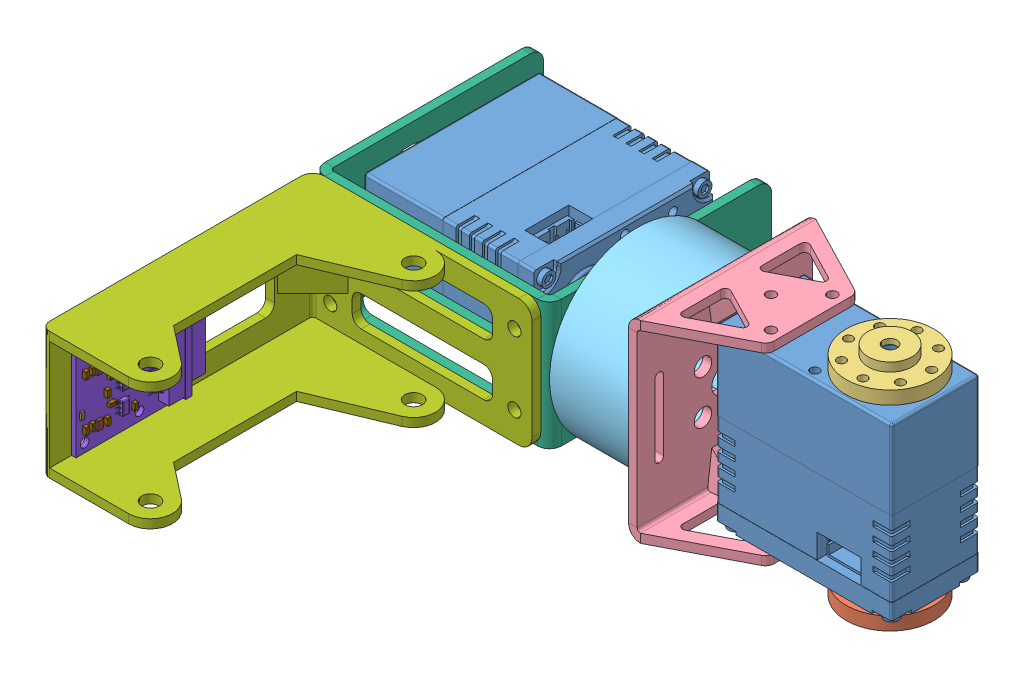
SolidWorks assembly wrist, configuration 默认. Lengths in mm.
Overall size (129.18 52.6 112.65).
74 component instances, 12 part files, 18 mates.
Components (placement in the parent):
- 舵机-1: 舵机 [默认] at origin size (43.48 52.6 27.66)
  - 舵机-1: 舵机 [默认] at origin size (40 51.4 20)
  - 副舵盘-1: 副舵盘 [默认] at (9.65 -0.8 0) x (-0.933258 0 -0.359207) z (-0.359207 0 0.933258) size (20 5 20)
  - 主舵盘-1: 主舵盘 [默认] at (9.65 40.8 0) x (0.838844 0 0.544372) z (-0.544372 0 0.838844) size (20 5 20)
- 短U支架-1: 短U支架 [默认] at (-28 20 0) x (0 1 0) z (0 0 -1) size (44 22 40)
- 45号舵机连接管-1: 45号舵机连接管 [默认] at (-48 20 0) x (0 -1 0) z (0 0 1) size (40 18 40)
- 转向舵机支架-1: 转向舵机支架 [默认] at (-75 20 18) x (1 0 0) z (0 -1 0) size (54 50.65 29)
- 舵机-2: 舵机 [默认] at (-60 20 -9.65) x (0 0 1) z (0 -1 0) size (40 51.4 20)
- 摄像头支架-1: 摄像头支架 [默认] at (-75 20 22) x (-1 0 0) z (0 1 0) size (52 62 29)
- 摄像头-1: 摄像头 [默认] at (-99 20 65) x (0 -1 0) z (0 0 -1) size (25 9.2 28)
  - 摄像头-1: 摄像头 [默认] at origin size (25 9.2 28)
  - 0603电容-2: 0603电容 [默认] at (-25.6955 -0.01 -49.0268) x (1 0 0) z (0 -1 0) size (1.6 0.82 0.82)
    - C_0603^0603电容-1: C_0603^0603电容 [默认] at (34.005 43.815 0) x (-1 0 0) z (0 0 1) size (1.6 0.82 0.82) (virtual)
      - C_0603-9^C_0603_0603电容-1: C_0603-9^C_0603_0603电容 [默认] at origin size (1.6 0.82 0.82) (virtual)
  - 0603电容-3: 0603电容 [默认] at (-42.3062 -0.01 -47.0667) x (1 0 0) z (0 -1 0) size (1.6 0.82 0.82)
    - C_0603^0603电容-1: C_0603^0603电容 [默认] at (34.005 43.815 0) x (-1 0 0) z (0 0 1) size (1.6 0.82 0.82) (virtual)
      - C_0603-9^C_0603_0603电容-1: C_0603-9^C_0603_0603电容 [默认] at origin size (1.6 0.82 0.82) (virtual)
  - 0603电容-7: 0603电容 [默认] at (49.2456 -0.01 -38.1328) x (0 0 1) z (0 -1 0) size (1.6 0.82 0.82)
    - C_0603^0603电容-1: C_0603^0603电容 [默认] at (34.005 43.815 0) x (-1 0 0) z (0 0 1) size (1.6 0.82 0.82) (virtual)
      - C_0603-9^C_0603_0603电容-1: C_0603-9^C_0603_0603电容 [默认] at origin size (1.6 0.82 0.82) (virtual)
  - 0603电容-10: 0603电容 [默认] at (-25.4606 -0.01 -42.7048) x (1 0 0) z (0 -1 0) size (1.6 0.82 0.82)
    - C_0603^0603电容-1: C_0603^0603电容 [默认] at (34.005 43.815 0) x (-1 0 0) z (0 0 1) size (1.6 0.82 0.82) (virtual)
      - C_0603-9^C_0603_0603电容-1: C_0603-9^C_0603_0603电容 [默认] at origin size (1.6 0.82 0.82) (virtual)
  - 0603电容-12: 0603电容 [默认] at (-26.2671 -0.01 -53.9256) x (1 0 0) z (0 -1 0) size (1.6 0.82 0.82)
    - C_0603^0603电容-1: C_0603^0603电容 [默认] at (34.005 43.815 0) x (-1 0 0) z (0 0 1) size (1.6 0.82 0.82) (virtual)
      - C_0603-9^C_0603_0603电容-1: C_0603-9^C_0603_0603电容 [默认] at origin size (1.6 0.82 0.82) (virtual)
  - 0805电容-1: 0805电容 [默认] at (51.4431 -0.01 78.819) x (-1 0 0) z (0 -1 0) size (1.22 2 0.52)
    - C_0805^0805电容-1: C_0805^0805电容 [默认] at (59.563 77.597 0) x (0 1 0) z (0 0 1) size (2 1.22 0.52) (virtual)
      - C_0805-5^C_0805_0805电容-1: C_0805-5^C_0805_0805电容 [默认] at origin size (2 1.22 0.52) (virtual)
  - 0805电阻-1: 0805电阻 [默认] at (115.7364 0 -119.6397) x (0 0 1) z (0 -1 0) size (1.25 2 0.5)
    - R_0805^0805电阻-1: R_0805^0805电阻 [默认] at (112.776 107.442 0) x (0 1 0) z (0 0 1) size (2 1.25 0.5) (virtual)
      - R_0805-21^R_0805_0805电阻-1: R_0805-21^R_0805_0805电阻 [默认] at origin size (2 1.25 0.5) (virtual)
  - 0603电阻-3: 0603电阻 [默认] at (118.0517 0 -149.4378) x (0 0 1) z (0 -1 0) size (0.8 1.6 0.4)
    - R_0603^0603电阻-1: R_0603^0603电阻 [默认] at (138.684 113.411 0) x (0 1 0) z (0 0 1) size (1.6 0.8 0.4) (virtual)
      - R_0603-25^R_0603_0603电阻-1: R_0603-25^R_0603_0603电阻 [默认] at origin size (1.6 0.8 0.4) (virtual)
  - 0603电阻-4: 0603电阻 [默认] at (-106.3314 1 -147.3108) x (0 0 1) z (0 1 0) size (0.8 1.6 0.4)
    - R_0603^0603电阻-1: R_0603^0603电阻 [默认] at (138.684 113.411 0) x (0 1 0) z (0 0 1) size (1.6 0.8 0.4) (virtual)
      - R_0603-25^R_0603_0603电阻-1: R_0603-25^R_0603_0603电阻 [默认] at origin size (1.6 0.8 0.4) (virtual)
  - 0603电阻-5: 0603电阻 [默认] at (134.1937 0 114.6319) x (-1 0 0) z (0 -1 0) size (0.8 1.6 0.4)
    - R_0603^0603电阻-1: R_0603^0603电阻 [默认] at (138.684 113.411 0) x (0 1 0) z (0 0 1) size (1.6 0.8 0.4) (virtual)
      - R_0603-25^R_0603_0603电阻-1: R_0603-25^R_0603_0603电阻 [默认] at origin size (1.6 0.8 0.4) (virtual)
  - 0603电容-14: 0603电容 [默认] at (-26.2671 -0.01 -52.4256) x (1 0 0) z (0 -1 0) size (1.6 0.82 0.82)
    - C_0603^0603电容-1: C_0603^0603电容 [默认] at (34.005 43.815 0) x (-1 0 0) z (0 0 1) size (1.6 0.82 0.82) (virtual)
      - C_0603-9^C_0603_0603电容-1: C_0603-9^C_0603_0603电容 [默认] at origin size (1.6 0.82 0.82) (virtual)
  - 0603电容-15: 0603电容 [默认] at (-30.4606 -0.01 -42.7048) x (1 0 0) z (0 -1 0) size (1.6 0.82 0.82)
    - C_0603^0603电容-1: C_0603^0603电容 [默认] at (34.005 43.815 0) x (-1 0 0) z (0 0 1) size (1.6 0.82 0.82) (virtual)
      - C_0603-9^C_0603_0603电容-1: C_0603-9^C_0603_0603电容 [默认] at origin size (1.6 0.82 0.82) (virtual)
  - 0603电容-16: 0603电容 [默认] at (-35.4606 -0.01 -42.7048) x (1 0 0) z (0 -1 0) size (1.6 0.82 0.82)
    - C_0603^0603电容-1: C_0603^0603电容 [默认] at (34.005 43.815 0) x (-1 0 0) z (0 0 1) size (1.6 0.82 0.82) (virtual)
      - C_0603-9^C_0603_0603电容-1: C_0603-9^C_0603_0603电容 [默认] at origin size (1.6 0.82 0.82) (virtual)
  - 0603电容-17: 0603电容 [默认] at (-37.2671 -0.01 -53.9256) x (1 0 0) z (0 -1 0) size (1.6 0.82 0.82)
    - C_0603^0603电容-1: C_0603^0603电容 [默认] at (34.005 43.815 0) x (-1 0 0) z (0 0 1) size (1.6 0.82 0.82) (virtual)
      - C_0603-9^C_0603_0603电容-1: C_0603-9^C_0603_0603电容 [默认] at origin size (1.6 0.82 0.82) (virtual)
  - 0603电容-18: 0603电容 [默认] at (-37.2671 -0.01 -52.4256) x (1 0 0) z (0 -1 0) size (1.6 0.82 0.82)
    - C_0603^0603电容-1: C_0603^0603电容 [默认] at (34.005 43.815 0) x (-1 0 0) z (0 0 1) size (1.6 0.82 0.82) (virtual)
      - C_0603-9^C_0603_0603电容-1: C_0603-9^C_0603_0603电容 [默认] at origin size (1.6 0.82 0.82) (virtual)
  - 0805电阻-2: 0805电阻 [默认] at (104.7364 0 -119.6397) x (0 0 1) z (0 -1 0) size (1.25 2 0.5)
    - R_0805^0805电阻-1: R_0805^0805电阻 [默认] at (112.776 107.442 0) x (0 1 0) z (0 0 1) size (2 1.25 0.5) (virtual)
      - R_0805-21^R_0805_0805电阻-1: R_0805-21^R_0805_0805电阻 [默认] at origin size (2 1.25 0.5) (virtual)
  - 0603电容-19: 0603电容 [默认] at (-31.1955 -0.01 -49.0268) x (1 0 0) z (0 -1 0) size (1.6 0.82 0.82)
    - C_0603^0603电容-1: C_0603^0603电容 [默认] at (34.005 43.815 0) x (-1 0 0) z (0 0 1) size (1.6 0.82 0.82) (virtual)
      - C_0603-9^C_0603_0603电容-1: C_0603-9^C_0603_0603电容 [默认] at origin size (1.6 0.82 0.82) (virtual)
  - 0603电容-20: 0603电容 [默认] at (-36.6955 -0.01 -49.0268) x (1 0 0) z (0 -1 0) size (1.6 0.82 0.82)
    - C_0603^0603电容-1: C_0603^0603电容 [默认] at (34.005 43.815 0) x (-1 0 0) z (0 0 1) size (1.6 0.82 0.82) (virtual)
      - C_0603-9^C_0603_0603电容-1: C_0603-9^C_0603_0603电容 [默认] at origin size (1.6 0.82 0.82) (virtual)
  - 0603电容-21: 0603电容 [默认] at (43.7456 -0.01 -38.1328) x (0 0 1) z (0 -1 0) size (1.6 0.82 0.82)
    - C_0603^0603电容-1: C_0603^0603电容 [默认] at (34.005 43.815 0) x (-1 0 0) z (0 0 1) size (1.6 0.82 0.82) (virtual)
      - C_0603-9^C_0603_0603电容-1: C_0603-9^C_0603_0603电容 [默认] at origin size (1.6 0.82 0.82) (virtual)
  - 0603电容-22: 0603电容 [默认] at (38.2456 -0.01 -38.1328) x (0 0 1) z (0 -1 0) size (1.6 0.82 0.82)
    - C_0603^0603电容-1: C_0603^0603电容 [默认] at (34.005 43.815 0) x (-1 0 0) z (0 0 1) size (1.6 0.82 0.82) (virtual)
      - C_0603-9^C_0603_0603电容-1: C_0603-9^C_0603_0603电容 [默认] at origin size (1.6 0.82 0.82) (virtual)
  - 0603电阻-6: 0603电阻 [默认] at (132.6937 0 114.6319) x (-1 0 0) z (0 -1 0) size (0.8 1.6 0.4)
    - R_0603^0603电阻-1: R_0603^0603电阻 [默认] at (138.684 113.411 0) x (0 1 0) z (0 0 1) size (1.6 0.8 0.4) (virtual)
      - R_0603-25^R_0603_0603电阻-1: R_0603-25^R_0603_0603电阻 [默认] at origin size (1.6 0.8 0.4) (virtual)
Mates (geometry in assembly coordinates):
- 重合1: coincident anti-aligned: plane of 舵机-1/舵机-1 through (0 0 0) normal (0 -1 0); plane of 短U支架-1 through (-28 0 0) normal (0 1 0)
- 同心1: concentric anti-aligned: circle of 舵机-1/舵机-1; circle of 短U支架-1
- 同心2: concentric anti-aligned: circle of 舵机-1/舵机-1; circle of 短U支架-1
- 重合2: coincident anti-aligned: plane of 短U支架-1 through (-30 20 0) normal (-1 0 0); plane of 60cm连接管-1 through (-30 20 0) normal (1 0 0)
- 同心3: concentric anti-aligned: circle of 短U支架-1; circle of 60cm连接管-1
- 同心4: concentric anti-aligned: circle of 短U支架-1; circle of 60cm连接管-1
- 重合5: coincident anti-aligned: plane of 60cm连接管-1 through (-48 20 0) normal (-1 0 0); plane of 转向舵机支架-1 through (-48 20 18) normal (1 0 0)
- 同心5: concentric aligned: circle of 转向舵机支架-1; circle of 60cm连接管-1
- 同心6: concentric aligned: circle of 60cm连接管-1; circle of 转向舵机支架-1
- 重合9: coincident anti-aligned: plane of 转向舵机支架-1 through (-100 20 18) normal (1 0 0); plane of 舵机-2 through (-100 20 -9.65) normal (-1 0 0)
- 同心7: concentric aligned: circle of 转向舵机支架-1; circle of 舵机-2
- 同心8: concentric aligned: circle of 转向舵机支架-1; circle of 舵机-2
- 重合11: coincident anti-aligned: plane of 转向舵机支架-1 through (-75 20 20) normal (0 0 1); plane of 摄像头支架-1 through (-75 20 20) normal (0 0 -1)
- 同心9: concentric aligned: circle of 转向舵机支架-1; circle of 摄像头支架-1
- 同心10: concentric aligned: circle of 转向舵机支架-1; circle of 摄像头支架-1
- 重合12: coincident anti-aligned: plane of 摄像头支架-1 through (-100 20 22) normal (1 0 0); plane of 摄像头-1/摄像头-1 through (-100 20 65) normal (-1 0 0)
- 同心11: concentric anti-aligned: circle of 摄像头支架-1; circle of 摄像头-1/摄像头-1
- 同心12: concentric anti-aligned: circle of 摄像头支架-1; circle of 摄像头-1/摄像头-1
